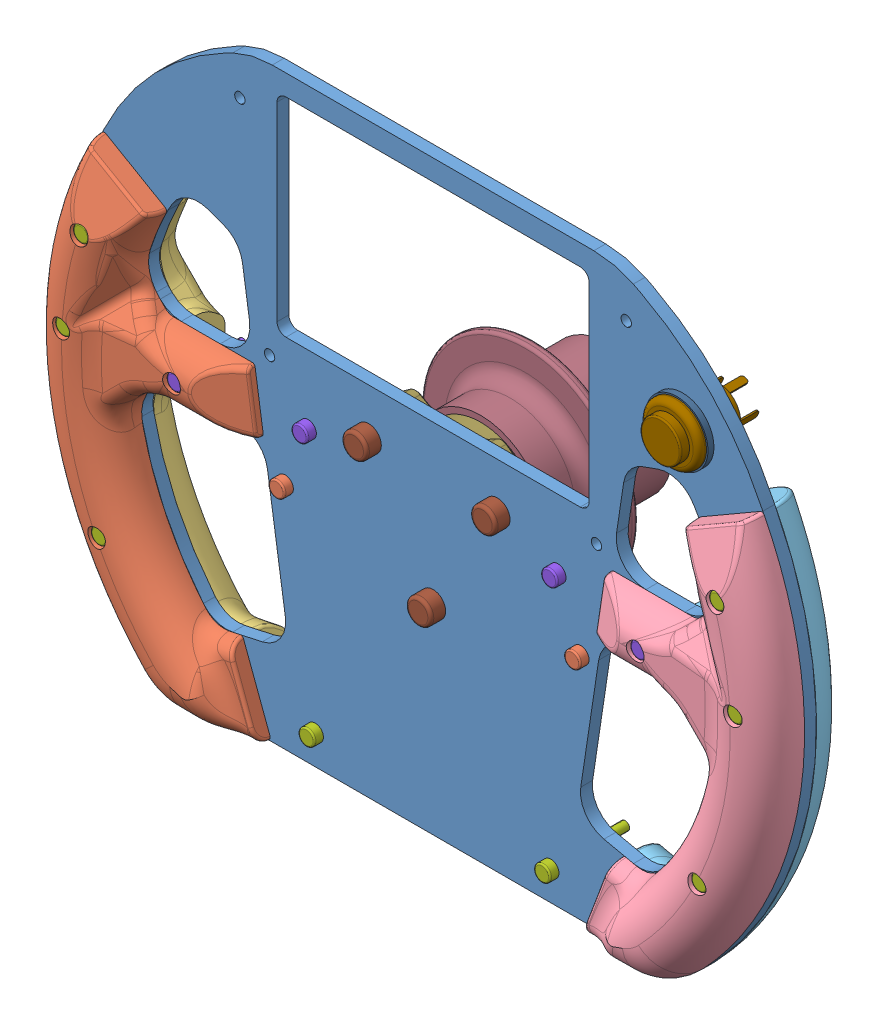
SolidWorks assembly RF019 SWCP&G, configuration ﾃﾞﾌｫﾙﾄ. Lengths in mm.
Overall size (580 763.75 72.95).
50 component instances, 20 part files, 77 mates.
Components (placement in the parent):
- RF019 SWCP kai-1: RF019 SWCP kai [ﾃﾞﾌｫﾙﾄ] at (-50.3349 -23.1318 252) size (250 250 4)
- RF019 SWG kai LF-1: RF019 SWG kai LF [ﾃﾞﾌｫﾙﾄ] at (-50.3349 -23.1318 252) size (580 763.75 26.45)
- RF019 SWG kai LR-1: RF019 SWG kai LR [ﾃﾞﾌｫﾙﾄ] at (-50.3349 -23.1318 248) size (580 763.75 28.68)
- RF019 SWG kai RF-1: RF019 SWG kai RF [ﾃﾞﾌｫﾙﾄ] at (-50.3349 -23.1318 252) size (580 763.75 26.45)
- RF019 SWG kai RR-1: RF019 SWG kai RR [ﾃﾞﾌｫﾙﾄ] at (-50.3349 -23.1318 248) size (580 763.75 29.22)
- M3 Nat-1: M3 Nat [ﾃﾞﾌｫﾙﾄ] at (-157.3349 11.8682 237.1) x (0.998944 0.04595 0) z (0 0 1) size (5.64 6.34 2.4)
- M3 Nat-2: M3 Nat [ﾃﾞﾌｫﾙﾄ] at (-163.3349 -18.1318 237.1) x (-0.539266 0.842136 0) z (0 0 1) size (5.64 6.34 2.4)
- M3 Nat-3: M3 Nat [ﾃﾞﾌｫﾙﾄ] at (-151.3349 -73.1318 237.1) x (0.998944 0.04595 0) z (0 0 1) size (5.64 6.34 2.4)
- M3 Nat-4: M3 Nat [ﾃﾞﾌｫﾙﾄ] at (56.6651 11.8682 237.1) x (0.998944 0.04595 0) z (0 0 1) size (5.64 6.34 2.4)
- M3 Nat-5: M3 Nat [ﾃﾞﾌｫﾙﾄ] at (62.6651 -18.1318 237.1) x (0.539266 -0.842136 0) z (0 0 1) size (5.64 6.34 2.4)
- M3 Nat-6: M3 Nat [ﾃﾞﾌｫﾙﾄ] at (50.6651 -73.1318 237.1) x (0.998944 0.04595 0) z (0 0 1) size (5.64 6.34 2.4)
- M3 25 Bolt-1: M3 25 Bolt [ﾃﾞﾌｫﾙﾄ] at (56.6651 11.8682 263.5) x (0.995541 0.094327 0) z (0 0 -1) size (5.5 5.5 28)
- M3 25 Bolt-2: M3 25 Bolt [ﾃﾞﾌｫﾙﾄ] at (-157.3349 11.8682 263.5) x (0.923728 0.383049 0) z (0 0 -1) size (5.5 5.5 28)
- M3 25 Bolt-3: M3 25 Bolt [ﾃﾞﾌｫﾙﾄ] at (-163.3349 -18.1318 263.5) x (0.923728 0.383049 0) z (0 0 -1) size (5.5 5.5 28)
- M3 25 Bolt-4: M3 25 Bolt [ﾃﾞﾌｫﾙﾄ] at (-151.3349 -73.1318 263.5) x (0.923728 0.383049 0) z (0 0 -1) size (5.5 5.5 28)
- M3 25 Bolt-5: M3 25 Bolt [ﾃﾞﾌｫﾙﾄ] at (50.6651 -73.1318 263.5) x (0.923728 0.383049 0) z (0 0 -1) size (5.5 5.5 28)
- M3 25 Bolt-6: M3 25 Bolt [ﾃﾞﾌｫﾙﾄ] at (62.6651 -18.1318 263.5) x (0.923728 0.383049 0) z (0 0 -1) size (5.5 5.5 28)
- M3 20 Bolt-1: M3 20 Bolt [ﾃﾞﾌｫﾙﾄ] at (-128.3349 -18.1318 261) x (0.923728 0.383049 0) z (0 0 -1) size (5.5 5.5 23)
- M3 20 Bolt-2: M3 20 Bolt [ﾃﾞﾌｫﾙﾄ] at (27.6651 -18.1318 261) x (0.923728 0.383049 0) z (0 0 -1) size (5.5 5.5 23)
- RF018 Paddle Shift Adapt Switch-1: RF018 Paddle Shift Adapt Switch [ﾃﾞﾌｫﾙﾄ] at (33.6651 44.8682 240) x (0.308889 0.951098 0) z (0 0 1) size (20 23.54 26.8)
- RF018 Spacer for PSA Switch-1: RF018 Spacer for PSA Switch [ﾃﾞﾌｫﾙﾄ] at (33.6651 44.8682 252) x (0.606194 0.795317 0) z (0 0 1) size (20.5 20.5 2)
- M3 20 Bolt-3: M3 20 Bolt [ﾃﾞﾌｫﾙﾄ] at (-92.3349 -18.1318 255) x (0.583085 -0.812411 0) z (0 0 -1) size (5.5 5.5 23)
- M3 20 Bolt-4: M3 20 Bolt [ﾃﾞﾌｫﾙﾄ] at (-8.3349 -18.1318 255) x (0.923728 0.383049 0) z (0 0 -1) size (5.5 5.5 23)
- M3 25 Bolt-7: M3 25 Bolt [ﾃﾞﾌｫﾙﾄ] at (-89.9626 -105.3898 255) x (0.923728 0.383049 0) z (0 0 -1) size (5.5 5.5 28)
- M3 25 Bolt-8: M3 25 Bolt [ﾃﾞﾌｫﾙﾄ] at (-10.7072 -105.3898 255) x (0.923728 0.383049 0) z (0 0 -1) size (5.5 5.5 28)
- M5 20 Bolt-1: M5 20 Bolt [ﾃﾞﾌｫﾙﾄ] at (-28.6843 -10.6318 257) x (-0.388877 -0.92129 0) z (0 0 -1) size (8.5 8.5 20)
- M5 20 Bolt-2: M5 20 Bolt [ﾃﾞﾌｫﾙﾄ] at (-71.9855 -10.6318 257) x (0.990277 0.139111 0) z (0 0 -1) size (8.5 8.5 20)
- M5 20 Bolt-3: M5 20 Bolt [ﾃﾞﾌｫﾙﾄ] at (-50.3349 -48.1318 257) x (0.943817 0.330469 0) z (0 0 -1) size (8.5 8.5 20)
- Quick Release 1-1: Quick Release 1 [ﾃﾞﾌｫﾙﾄ] at (-54.124 -40.0834 338) x (-0.5 -0.866025 0) z (0 0 -1) size (80.66 80.66 55)
  - 1-1-1: 1-1 [ﾃﾞﾌｫﾙﾄ] at (-16.575 5.1943 90) size (59.95 55.8 55)
  - 1-2-1: 1-2 [ﾃﾞﾌｫﾙﾄ] at (-16.575 5.1943 102) x (-0.986103 -0.166135 0) z (0 0 1) size (70 70 43)
  - 1-3-1: 1-3 [ﾃﾞﾌｫﾙﾄ] at (-16.575 5.1943 145) x (-0.997775 -0.066677 0) z (0 0 -1) size (40 40 20)
  - 1-5-1: 1-5 [ﾃﾞﾌｫﾙﾄ] at (-16.575 5.1943 134.5) x (-0.836075 -0.548615 0) z (0 0 -1) size (25 25 10)
  - 1-4-1: 1-4 [ﾃﾞﾌｫﾙﾄ] at (-23.9223 -4.9184 137) size (5 5 5)
  - 1-4-2: 1-4 [ﾃﾞﾌｫﾙﾄ] at (-16.575 -7.3057 137) x (0.757505 -0.002014 -0.652826) z (0.259947 -0.91637 0.304457) size (5 5 5)
  - 1-4-4: 1-4 [ﾃﾞﾌｫﾙﾄ] at (-9.2277 -4.9184 137) x (0.59978 -0.145312 0.78686) z (-0.610771 0.552153 0.567525) size (5 5 5)
  - 1-4-5: 1-4 [ﾃﾞﾌｫﾙﾄ] at (-4.6868 1.3316 137) x (0.883022 0.321394 -0.34202) z (0.418989 -0.211471 0.883022) size (5 5 5)
  - 1-4-6: 1-4 [ﾃﾞﾌｫﾙﾄ] at (-28.4632 1.3316 137) x (0.720478 0.501888 -0.47856) z (0.592115 -0.085992 0.801253) size (5 5 5)
  - 1-4-7: 1-4 [ﾃﾞﾌｫﾙﾄ] at (-4.6868 9.057 137) x (0.586824 0.492404 -0.642788) z (0.790379 -0.175893 0.586824) size (5 5 5)
  - 1-4-12: 1-4 [ﾃﾞﾌｫﾙﾄ] at (-9.2277 15.307 137) x (0.37191 0.671322 -0.6411) z (0.907926 -0.119274 0.401802) size (5 5 5)
  - 1-4-13: 1-4 [ﾃﾞﾌｫﾙﾄ] at (-16.575 17.6943 137) x (0.144729 0.779036 -0.610046) z (0.980991 -0.032428 0.191322) size (5 5 5)
  - 1-4-16: 1-4 [ﾃﾞﾌｫﾙﾄ] at (-23.9223 15.307 137) x (-0.090859 0.870583 -0.48356) z (0.993983 0.109103 0.00966) size (5 5 5)
  - 1-4-17: 1-4 [ﾃﾞﾌｫﾙﾄ] at (-28.4632 9.057 137) x (-0.407074 0.843286 -0.350941) z (0.912107 0.354897 -0.205205) size (5 5 5)
  - Spring 1-1: Spring 1 [ﾃﾞﾌｫﾙﾄ] at (-16.575 5.1943 116) size (37.17 37.65 10)
  - Spring 2-1: Spring 2 [ﾃﾞﾌｫﾙﾄ] at (-16.575 5.1943 104) size (22.6 22.92 21.5)
- M5 Nat-1: M5 Nat [ﾃﾞﾌｫﾙﾄ] at (-28.6843 -10.6318 239) x (0.511027 -0.859565 0) z (0 0 1) size (8.32 9.21 4)
- M5 Nat-2: M5 Nat [ﾃﾞﾌｫﾙﾄ] at (-71.9855 -10.6318 239) x (0.959837 -0.280558 0) z (0 0 1) size (8.32 9.21 4)
- M5 Nat-3: M5 Nat [ﾃﾞﾌｫﾙﾄ] at (-50.3349 -48.1318 239) x (-0.606129 -0.795367 0) z (0 0 1) size (8.32 9.21 4)
- M3 15 Bolt-1: M3 15 Bolt [ﾃﾞﾌｫﾙﾄ] at (-100.0734 -38.1318 255) x (0.923728 0.383049 0) z (0 0 -1) size (5.5 5.5 18)
- M3 15 Bolt-2: M3 15 Bolt [ﾃﾞﾌｫﾙﾄ] at (-0.5964 -38.1318 255) x (-0.918666 0.395034 0) z (0 0 -1) size (5.5 5.5 18)
Mates (geometry in assembly coordinates):
- 同心円1: concentric aligned: cylinder of RF019 SWCP kai-1 through (-157.3349 11.8682 242) axis (0 0 1) radius 1.75; cylinder of RF019 SWG kai LF-1 through (-157.3349 11.8682 224.5) axis (0 0 1) radius 1.75
- 同心円2: concentric aligned: cylinder of RF019 SWCP kai-1 through (-151.3349 -73.1318 242) axis (0 0 1) radius 1.75; cylinder of RF019 SWG kai LF-1 through (-151.3349 -73.1318 224.5) axis (0 0 1) radius 1.75
- 一致1: coincident anti-aligned: plane of RF019 SWCP kai-1 through (-50.3349 -23.1318 252) normal (0 0 1); plane of RF019 SWG kai LF-1 through (-50.3349 -23.1318 252) normal (0 0 -1)
- 同心円3: concentric aligned: cylinder of RF019 SWCP kai-1 through (-157.3349 11.8682 242) axis (0 0 1) radius 1.75; cylinder of RF019 SWG kai LR-1 through (-157.3349 11.8682 220.5) axis (0 0 1) radius 1.75
- 同心円4: concentric aligned: cylinder of RF019 SWCP kai-1 through (-151.3349 -73.1318 242) axis (0 0 1) radius 1.75; cylinder of RF019 SWG kai LR-1 through (-151.3349 -73.1318 220.5) axis (0 0 1) radius 1.75
- 一致2: coincident anti-aligned: plane of RF019 SWCP kai-1 through (-50.3349 -23.1318 248) normal (0 0 -1); plane of RF019 SWG kai LR-1 through (-50.3349 -23.1318 248) normal (0 0 1)
- 同心円5: concentric aligned: cylinder of RF019 SWCP kai-1 through (56.6651 11.8682 242) axis (0 0 1) radius 1.75; cylinder of RF019 SWG kai RF-1 through (56.6651 11.8682 224.5) axis (0 0 1) radius 1.75
- 同心円6: concentric aligned: cylinder of RF019 SWCP kai-1 through (50.6651 -73.1318 242) axis (0 0 1) radius 1.75; cylinder of RF019 SWG kai RF-1 through (50.6651 -73.1318 224.5) axis (0 0 1) radius 1.75
- 一致3: coincident anti-aligned: plane of RF019 SWCP kai-1 through (-50.3349 -23.1318 252) normal (0 0 1); plane of RF019 SWG kai RF-1 through (-50.3349 -23.1318 252) normal (0 0 -1)
- 同心円7: concentric aligned: cylinder of RF019 SWCP kai-1 through (56.6651 11.8682 242) axis (0 0 1) radius 1.75; cylinder of RF019 SWG kai RR-1 through (56.6651 11.8682 220.5) axis (0 0 1) radius 1.75
- 同心円8: concentric aligned: cylinder of RF019 SWCP kai-1 through (50.6651 -73.1318 242) axis (0 0 1) radius 1.75; cylinder of RF019 SWG kai RR-1 through (50.6651 -73.1318 220.5) axis (0 0 1) radius 1.75
- 一致4: coincident anti-aligned: plane of RF019 SWCP kai-1 through (-50.3349 -23.1318 248) normal (0 0 -1); plane of RF019 SWG kai RR-1 through (-50.3349 -23.1318 248) normal (0 0 1)
- 同心円9: concentric anti-aligned: cylinder of RF019 SWG kai LR-1 through (-157.3349 11.8682 220.5) axis (0 0 1) radius 1.75; cylinder of M3 Nat-1 through (-157.3349 11.8682 239.5) axis (0 0 -1) radius 1.5
- 一致5: coincident anti-aligned: plane of RF019 SWG kai LR-1 through (-50.3349 -23.1318 239.5) normal (0 0 -1); plane of M3 Nat-1 through (-157.3349 11.8682 239.5) normal (0 0 1)
- 平行1: parallel anti-aligned: plane of RF019 SWG kai LR-1 through (-160.2099 10.2083 239.5) normal (1 0 0); plane of M3 Nat-1 through (-160.0849 13.4559 239.5) normal (-1 0 0)
- 同心円10: concentric anti-aligned: cylinder of RF019 SWG kai LR-1 through (-163.3349 -18.1318 220.5) axis (0 0 1) radius 1.75; cylinder of M3 Nat-2 through (-163.3349 -18.1318 239.5) axis (0 0 -1) radius 1.5
- 一致7: coincident anti-aligned: plane of RF019 SWG kai LR-1 through (-50.3349 -23.1318 239.5) normal (0 0 -1); plane of M3 Nat-2 through (-163.3349 -18.1318 239.5) normal (0 0 1)
- 平行2: parallel anti-aligned: plane of RF019 SWG kai LR-1 through (-163.3349 -21.4516 239.5) normal (0.5 0.866025 0); plane of M3 Nat-2 through (-166.0849 -19.7196 239.5) normal (-0.5 -0.866025 0)
- 同心円11: concentric anti-aligned: cylinder of RF019 SWG kai LR-1 through (-151.3349 -73.1318 220.5) axis (0 0 1) radius 1.75; cylinder of M3 Nat-3 through (-151.3349 -73.1318 239.5) axis (0 0 -1) radius 1.5
- 一致9: coincident anti-aligned: plane of RF019 SWG kai LR-1 through (-50.3349 -23.1318 239.5) normal (0 0 -1); plane of M3 Nat-3 through (-151.3349 -73.1318 239.5) normal (0 0 1)
- 平行3: parallel anti-aligned: plane of RF019 SWG kai LR-1 through (-154.2099 -74.7917 239.5) normal (1 0 0); plane of M3 Nat-3 through (-154.0849 -71.5441 239.5) normal (-1 0 0)
- 同心円12: concentric anti-aligned: cylinder of RF019 SWG kai RR-1 through (56.6651 11.8682 220.5) axis (0 0 1) radius 1.75; cylinder of M3 Nat-4 through (56.6651 11.8682 239.5) axis (0 0 -1) radius 1.5
- 一致11: coincident anti-aligned: plane of RF019 SWG kai RR-1 through (-50.3349 -23.1318 239.5) normal (0 0 -1); plane of M3 Nat-4 through (56.6651 11.8682 239.5) normal (0 0 1)
- 平行4: parallel anti-aligned: plane of RF019 SWG kai RR-1 through (59.5401 13.528 239.5) normal (-0.5 -0.866025 0); plane of M3 Nat-4 through (59.4151 13.4559 239.5) normal (0.5 0.866025 0)
- 同心円13: concentric anti-aligned: cylinder of RF019 SWG kai RR-1 through (62.6651 -18.1318 220.5) axis (0 0 1) radius 1.75; cylinder of M3 Nat-5 through (62.6651 -18.1318 239.5) axis (0 0 -1) radius 1.5
- 一致13: coincident anti-aligned: plane of RF019 SWG kai RR-1 through (-50.3349 -23.1318 239.5) normal (0 0 -1); plane of M3 Nat-5 through (62.6651 -18.1318 239.5) normal (0 0 1)
- 平行5: parallel anti-aligned: plane of RF019 SWG kai RR-1 through (59.7901 -19.7917 239.5) normal (0.5 0.866025 0); plane of M3 Nat-5 through (59.9151 -19.7196 239.5) normal (-0.5 -0.866025 0)
- 同心円14: concentric anti-aligned: cylinder of RF019 SWG kai RR-1 through (50.6651 -73.1318 220.5) axis (0 0 1) radius 1.75; cylinder of M3 Nat-6 through (50.6651 -73.1318 239.5) axis (0 0 -1) radius 1.5
- 一致15: coincident anti-aligned: plane of RF019 SWG kai RR-1 through (-50.3349 -23.1318 239.5) normal (0 0 -1); plane of M3 Nat-6 through (50.6651 -73.1318 239.5) normal (0 0 1)
- 平行6: parallel anti-aligned: plane of RF019 SWG kai RR-1 through (53.5401 -74.7917 239.5) normal (-1 0 0); plane of M3 Nat-6 through (53.4151 -74.7196 239.5) normal (1 0 0)
- 同心円15: concentric aligned: cylinder of RF019 SWG kai RF-1 through (56.6651 11.8682 224.5) axis (0 0 1) radius 1.75; cylinder of M3 25 Bolt-1 through (56.6651 11.8682 235.5) axis (0 0 1) radius 1.5
- 一致17: coincident anti-aligned: plane of RF019 SWG kai RF-1 through (56.6651 11.8682 260.5) normal (0 0 1); plane of M3 25 Bolt-1 through (56.6651 11.8682 260.5) normal (0 0 -1)
- 同心円16: concentric aligned: cylinder of RF019 SWG kai RF-1 through (62.6651 -18.1318 224.5) axis (0 0 1) radius 1.75; cylinder of M3 25 Bolt-6 through (62.6651 -18.1318 235.5) axis (0 0 1) radius 1.5
- 一致18: coincident anti-aligned: plane of RF019 SWG kai RF-1 through (62.6651 -18.1318 260.5) normal (0 0 1); plane of M3 25 Bolt-6 through (62.6651 -18.1318 260.5) normal (0 0 -1)
- 同心円17: concentric aligned: cylinder of M3 25 Bolt-5 through (50.6651 -73.1318 235.5) axis (0 0 1) radius 1.5; cylinder of RF019 SWG kai RF-1 through (50.6651 -73.1318 224.5) axis (0 0 1) radius 1.75
- 一致19: coincident anti-aligned: plane of RF019 SWG kai RF-1 through (50.6651 -73.1318 260.5) normal (0 0 1); plane of M3 25 Bolt-5 through (50.6651 -73.1318 260.5) normal (0 0 -1)
- 同心円18: concentric aligned: cylinder of RF019 SWG kai LF-1 through (-157.3349 11.8682 224.5) axis (0 0 1) radius 1.75; cylinder of M3 25 Bolt-2 through (-157.3349 11.8682 235.5) axis (0 0 1) radius 1.5
- 一致20: coincident anti-aligned: plane of RF019 SWG kai LF-1 through (-157.3349 11.8682 260.5) normal (0 0 1); plane of M3 25 Bolt-2 through (-157.3349 11.8682 260.5) normal (0 0 -1)
- 同心円19: concentric aligned: cylinder of RF019 SWG kai LF-1 through (-163.3349 -18.1318 224.5) axis (0 0 1) radius 1.75; cylinder of M3 25 Bolt-3 through (-163.3349 -18.1318 235.5) axis (0 0 1) radius 1.5
- 一致21: coincident anti-aligned: plane of RF019 SWG kai LF-1 through (-163.3349 -18.1318 260.5) normal (0 0 1); plane of M3 25 Bolt-3 through (-163.3349 -18.1318 260.5) normal (0 0 -1)
- 同心円20: concentric aligned: cylinder of RF019 SWG kai LF-1 through (-151.3349 -73.1318 224.5) axis (0 0 1) radius 1.75; cylinder of M3 25 Bolt-4 through (-151.3349 -73.1318 235.5) axis (0 0 1) radius 1.5
- 一致22: coincident anti-aligned: plane of RF019 SWG kai LF-1 through (-151.3349 -73.1318 260.5) normal (0 0 1); plane of M3 25 Bolt-4 through (-151.3349 -73.1318 260.5) normal (0 0 -1)
- 同心円21: concentric aligned: cylinder of RF019 SWG kai LF-1 through (-128.3349 -18.1318 224.5) axis (0 0 1) radius 1.75; cylinder of M3 20 Bolt-1 through (-128.3349 -18.1318 238) axis (0 0 1) radius 1.5
- 一致23: coincident anti-aligned: plane of RF019 SWG kai LF-1 through (-128.3349 -18.1318 258) normal (0 0 1); plane of M3 20 Bolt-1 through (-128.3349 -18.1318 258) normal (0 0 -1)
- 同心円22: concentric aligned: cylinder of RF019 SWG kai RF-1 through (27.6651 -18.1318 224.5) axis (0 0 1) radius 1.75; cylinder of M3 20 Bolt-2 through (27.6651 -18.1318 238) axis (0 0 1) radius 1.5
- 一致24: coincident anti-aligned: plane of RF019 SWG kai RF-1 through (27.6651 -18.1318 258) normal (0 0 1); plane of M3 20 Bolt-2 through (27.6651 -18.1318 258) normal (0 0 -1)
- 同心円23: concentric anti-aligned: cylinder of RF019 SWCP kai-1 through (33.6651 44.8682 242) axis (0 0 1) radius 8.25; cylinder of RF018 Spacer for PSA Switch-1 through (33.6651 44.8682 254) axis (0 0 -1) radius 8.25
- 一致25: coincident anti-aligned: plane of RF019 SWCP kai-1 through (-50.3349 -23.1318 252) normal (0 0 1); plane of RF018 Spacer for PSA Switch-1 through (33.6651 44.8682 252) normal (0 0 -1)
- 同心円24: concentric anti-aligned: cylinder of RF018 Paddle Shift Adapt Switch-1 through (33.6651 44.8682 254) axis (0 0 -1) radius 7.5; cylinder of RF019 SWCP kai-1 through (33.6651 44.8682 242) axis (0 0 1) radius 8.25
- 一致26: coincident anti-aligned: plane of RF018 Paddle Shift Adapt Switch-1 through (33.6651 44.8682 254) normal (0 0 -1); plane of RF018 Spacer for PSA Switch-1 through (33.6651 44.8682 254) normal (0 0 1)
- 同心円25: concentric aligned: cylinder of RF019 SWCP kai-1 through (-92.3349 -18.1318 242) axis (0 0 1) radius 1.75; cylinder of M3 20 Bolt-3 through (-92.3349 -18.1318 232) axis (0 0 1) radius 1.5
- 一致27: coincident anti-aligned: plane of RF019 SWCP kai-1 through (-50.3349 -23.1318 252) normal (0 0 1); plane of M3 20 Bolt-3 through (-92.3349 -18.1318 252) normal (0 0 -1)
- 同心円26: concentric aligned: cylinder of RF019 SWCP kai-1 through (-8.3349 -18.1318 242) axis (0 0 1) radius 1.75; cylinder of M3 20 Bolt-4 through (-8.3349 -18.1318 232) axis (0 0 1) radius 1.5
- 一致28: coincident anti-aligned: plane of RF019 SWCP kai-1 through (-50.3349 -23.1318 252) normal (0 0 1); plane of M3 20 Bolt-4 through (-8.3349 -18.1318 252) normal (0 0 -1)
- 同心円27: concentric aligned: cylinder of RF019 SWCP kai-1 through (-100.0734 -38.1318 242) axis (0 0 1) radius 1.75; cylinder of M3 15 Bolt-1 through (-100.0734 -38.1318 237) axis (0 0 1) radius 1.5
- 一致29: coincident anti-aligned: plane of RF019 SWCP kai-1 through (-50.3349 -23.1318 252) normal (0 0 1); plane of M3 15 Bolt-1 through (-100.0734 -38.1318 252) normal (0 0 -1)
- 同心円28: concentric aligned: cylinder of RF019 SWCP kai-1 through (-0.5964 -38.1318 242) axis (0 0 1) radius 1.75; cylinder of M3 15 Bolt-2 through (-0.5964 -38.1318 237) axis (0 0 1) radius 1.5
- 一致30: coincident anti-aligned: plane of RF019 SWCP kai-1 through (-50.3349 -23.1318 252) normal (0 0 1); plane of M3 15 Bolt-2 through (-0.5964 -38.1318 252) normal (0 0 -1)
- 同心円29: concentric aligned: cylinder of RF019 SWCP kai-1 through (-89.9626 -105.3898 242) axis (0 0 1) radius 1.75; cylinder of M3 25 Bolt-7 through (-89.9626 -105.3898 227) axis (0 0 1) radius 1.5
- 一致31: coincident anti-aligned: plane of RF019 SWCP kai-1 through (-50.3349 -23.1318 252) normal (0 0 1); plane of M3 25 Bolt-7 through (-89.9626 -105.3898 252) normal (0 0 -1)
- 同心円30: concentric aligned: cylinder of RF019 SWCP kai-1 through (-10.7072 -105.3898 242) axis (0 0 1) radius 1.75; cylinder of M3 25 Bolt-8 through (-10.7072 -105.3898 227) axis (0 0 1) radius 1.5
- 一致32: coincident anti-aligned: plane of RF019 SWCP kai-1 through (-50.3349 -23.1318 252) normal (0 0 1); plane of M3 25 Bolt-8 through (-10.7072 -105.3898 252) normal (0 0 -1)
- 同心円31: concentric aligned: cylinder of RF019 SWCP kai-1 through (-50.3349 -48.1318 242) axis (0 0 1) radius 2.75; cylinder of M5 20 Bolt-3 through (-50.3349 -48.1318 237) axis (0 0 1) radius 2.5
- 一致33: coincident anti-aligned: plane of RF019 SWCP kai-1 through (-50.3349 -23.1318 252) normal (0 0 1); plane of M5 20 Bolt-3 through (-50.3349 -48.1318 252) normal (0 0 -1)
- 同心円32: concentric aligned: cylinder of RF019 SWCP kai-1 through (-71.9855 -10.6318 242) axis (0 0 1) radius 2.75; cylinder of M5 20 Bolt-2 through (-71.9855 -10.6318 237) axis (0 0 1) radius 2.5
- 一致34: coincident anti-aligned: plane of RF019 SWCP kai-1 through (-50.3349 -23.1318 252) normal (0 0 1); plane of M5 20 Bolt-2 through (-71.9855 -10.6318 252) normal (0 0 -1)
- 同心円33: concentric aligned: cylinder of RF019 SWCP kai-1 through (-28.6843 -10.6318 242) axis (0 0 1) radius 2.75; cylinder of M5 20 Bolt-1 through (-28.6843 -10.6318 237) axis (0 0 1) radius 2.5
- 一致35: coincident anti-aligned: plane of RF019 SWCP kai-1 through (-50.3349 -23.1318 252) normal (0 0 1); plane of M5 20 Bolt-1 through (-28.6843 -10.6318 252) normal (0 0 -1)
- 同心円34: concentric aligned: cylinder of M5 20 Bolt-2 through (-71.9855 -10.6318 237) axis (0 0 1) radius 2.5; cylinder of Quick Release 1-1/1-1-1 through (-71.9855 -10.6318 243) axis (0 0 1) radius 2.1
- 一致36: coincident anti-aligned: plane of RF019 SWCP kai-1 through (-50.3349 -23.1318 248) normal (0 0 -1); plane of Quick Release 1-1/1-1-1 through (-50.3349 -23.1318 248) normal (0 0 1)
- 同心円36: concentric aligned: cylinder of M5 20 Bolt-3 through (-50.3349 -48.1318 237) axis (0 0 1) radius 2.5; cylinder of Quick Release 1-1/1-1-1 through (-50.3349 -48.1318 243) axis (0 0 1) radius 2.1
- 同心円37: concentric anti-aligned: cylinder of M5 20 Bolt-1 through (-28.6843 -10.6318 237) axis (0 0 1) radius 2.5; cylinder of M5 Nat-1 through (-28.6843 -10.6318 243) axis (0 0 -1) radius 2.5
- 一致37: coincident anti-aligned: plane of Quick Release 1-1/1-1-1 through (-50.3349 -23.1318 243) normal (0 0 -1); plane of M5 Nat-1 through (-28.6843 -10.6318 243) normal (0 0 1)
- 同心円38: concentric anti-aligned: cylinder of M5 20 Bolt-2 through (-71.9855 -10.6318 237) axis (0 0 1) radius 2.5; cylinder of M5 Nat-2 through (-71.9855 -10.6318 243) axis (0 0 -1) radius 2.5
- 一致38: coincident anti-aligned: plane of Quick Release 1-1/1-1-1 through (-50.3349 -23.1318 243) normal (0 0 -1); plane of M5 Nat-2 through (-71.9855 -10.6318 243) normal (0 0 1)
- 同心円39: concentric anti-aligned: cylinder of M5 20 Bolt-3 through (-50.3349 -48.1318 237) axis (0 0 1) radius 2.5; cylinder of M5 Nat-3 through (-50.3349 -48.1318 243) axis (0 0 -1) radius 2.5
- 一致39: coincident anti-aligned: plane of Quick Release 1-1/1-1-1 through (-50.3349 -23.1318 243) normal (0 0 -1); plane of M5 Nat-3 through (-50.3349 -48.1318 243) normal (0 0 1)
